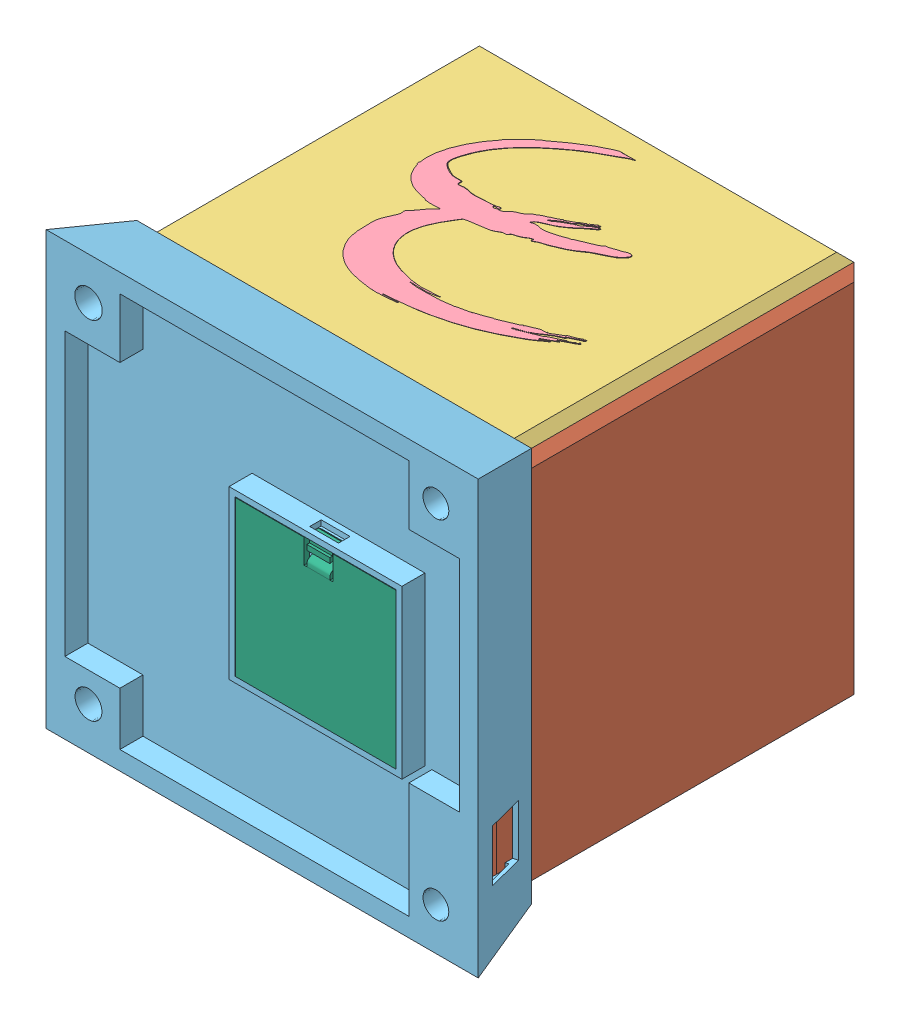
SolidWorks assembly grand_cube, configuration Défaut. Lengths in mm.
Overall size (150 150 143.02).
8 component instances, 6 part files, 19 mates.
Components (placement in the parent):
- cote_cubeb_top-1: cote_cubeb_top [Défaut] at (-79.2888 -63.7392 130.0001) size (130 130 17.9)
- cote_cubeb_1-6: cote_cubeb_1 [Défaut] at (50.7112 -66.7392 133.0001) x (-1 0 0) z (0 1 0) size (130 130 13)
- cote_cubeb_1-5: cote_cubeb_1 [Défaut] at (53.7112 66.2608 132.9001) x (0 -1 0) z (-1 0 0) size (130 130 13)
- cote_cubeb_1-7: cote_cubeb_1 [Défaut] at (-82.2888 -63.7392 132.9001) x (0 1 0) z (1 0 0) size (130 130 13)
- cote_cubeb_1_espilon-4: cote_cubeb_1_espilon [Défaut] at (-79.2888 69.2608 132.9001) x (1 0 0) z (0 -1 0) size (130 130 13)
- epsilon_rouge-1: epsilon_rouge [Défaut] at (-11.9946 66.2608 185.5182) x (-0.999984 0 0.005736) z (0 1 0) size (85.8 85.09 3)
- cote_cubeb_bot-2: cote_cubeb_bot [Défaut] at (-89.5888 75.9608 273.0001) x (1 0 0) z (0 0 -1) size (150 150 25)
- cache_pile-1: cache_pile [Défaut] at (-23.8888 -25.5392 273.0001) x (0 1 0) z (0 0 -1) size (57 55.8 11.51)
Mates (geometry in assembly coordinates):
- Coïncidente2: coincident anti-aligned: plane of cote_cubeb_top-1 through (-79.2888 -63.7392 147.9001) normal (0 0 1); plane of cote_cubeb_1-5 through (40.7112 66.2608 147.9001) normal (0 0 -1)
- Coaxiale1: concentric aligned: cylinder of cote_cubeb_top-1 through (45.7112 61.2608 147.9001) axis (0 0 -1) radius 1.55; cylinder of cote_cubeb_1-5 through (45.7112 61.2608 262.9001) axis (0 0 -1) radius 1.75
- Coïncidente3: coincident aligned: plane of cote_cubeb_top-1 through (40.7112 66.2608 147.9001) normal (-1 0 0); plane of cote_cubeb_1-5 through (40.7112 66.2608 132.9001) normal (-1 0 0)
- Coaxiale2: concentric aligned: cylinder of cote_cubeb_1-6 through (45.7112 -58.7392 263.0001) axis (0 0 -1) radius 1.75; cylinder of cote_cubeb_1-5 through (45.7112 -58.7392 262.9001) axis (0 0 -1) radius 1.75
- Coïncidente4: coincident anti-aligned: plane of cote_cubeb_1-6 through (50.7112 -53.7392 153.0001) normal (0 0 1); plane of cote_cubeb_1-5 through (40.7112 -63.7392 153.0001) normal (0 0 -1)
- Coïncidente5: coincident aligned: plane of cote_cubeb_top-1 through (50.7112 -53.7392 147.9001) normal (0 1 0); plane of cote_cubeb_1-6 through (50.7112 -53.7392 133.0001) normal (0 1 0)
- Coaxiale4: concentric aligned: cylinder of cote_cubeb_1-6 through (-74.2888 -58.7392 263.0001) axis (0 0 -1) radius 1.75; cylinder of cote_cubeb_1-7 through (-74.2888 -58.7392 262.9001) axis (0 0 -1) radius 1.75
- Coïncidente9: coincident aligned: plane of cote_cubeb_1-6 through (-69.2888 -53.7392 153.1001) normal (1 0 0); plane of cote_cubeb_1-7 through (-69.2888 -63.7392 132.9001) normal (1 0 0)
- Coïncidente10: coincident anti-aligned: plane of cote_cubeb_top-1 through (-79.2888 -63.7392 147.9001) normal (0 0 1); plane of cote_cubeb_1-7 through (-69.2888 -63.7392 147.9001) normal (0 0 -1)
- Coaxiale5: concentric aligned: cylinder of cote_cubeb_1-7 through (-74.2888 61.2608 262.9001) axis (0 0 -1) radius 1.75; cylinder of cote_cubeb_1_espilon-4 through (-74.2888 61.2608 262.9001) axis (0 0 -1) radius 1.75
- Coïncidente11: coincident anti-aligned: plane of cote_cubeb_top-1 through (-79.2888 -63.7392 147.9001) normal (0 0 1); plane of cote_cubeb_1_espilon-4 through (-79.2888 56.2608 147.9001) normal (0 0 -1)
- Coïncidente12: coincident aligned: plane of cote_cubeb_1_espilon-4 through (-79.2888 69.2608 132.9001) normal (0 1 0); plane of epsilon_rouge-1 through (13.0087 69.2608 172.2946) normal (0 1 0)
- Parallèle3: parallel aligned: plane of cote_cubeb_1-7 through (-69.2888 -63.7392 132.9001) normal (1 0 0); plane of cote_cubeb_1_espilon-4 through (-69.2888 56.2608 152.9001) normal (1 0 0)
- Coaxiale6: concentric aligned: cylinder of cote_cubeb_1_espilon-4 through (45.7112 61.2608 262.9001) axis (0 0 -1) radius 1.75; cylinder of cote_cubeb_bot-2 through (45.7112 61.2608 263.0001) axis (0 0 -1) radius 1.75
- Parallèle4: parallel aligned: plane of cote_cubeb_1-5 through (50.7112 66.2608 132.9001) normal (-1 0 0); plane of cote_cubeb_bot-2 through (53.9112 75.9608 265.0001) normal (-1 0 0)
- Coïncidente14: coincident anti-aligned: plane of cote_cubeb_1-6 through (-79.2888 -53.7392 248.0001) normal (0 0 1); plane of cote_cubeb_bot-2 through (-89.5888 75.9608 248.0001) normal (0 0 -1)
- Coïncidente15: coincident aligned: plane of cote_cubeb_bot-2 through (-89.5888 75.9608 273.0001) normal (0 0 1); plane of cache_pile-1 through (-23.8888 -25.5392 273.0001) normal (0 0 1)
- Coïncidente17: coincident: plane of cote_cubeb_bot-2 through (31.9112 75.9608 265.0001) normal (-1 0 0); plane of cache_pile-1 through (31.9112 -25.5392 271.0001) normal (1 0 0)
- Coïncidente18: coincident: plane of cote_cubeb_bot-2 through (-89.5888 -25.5392 265.0001) normal (0 1 0); plane of cache_pile-1 through (-23.8888 -25.5392 271.0001) normal (0 -1 0)
